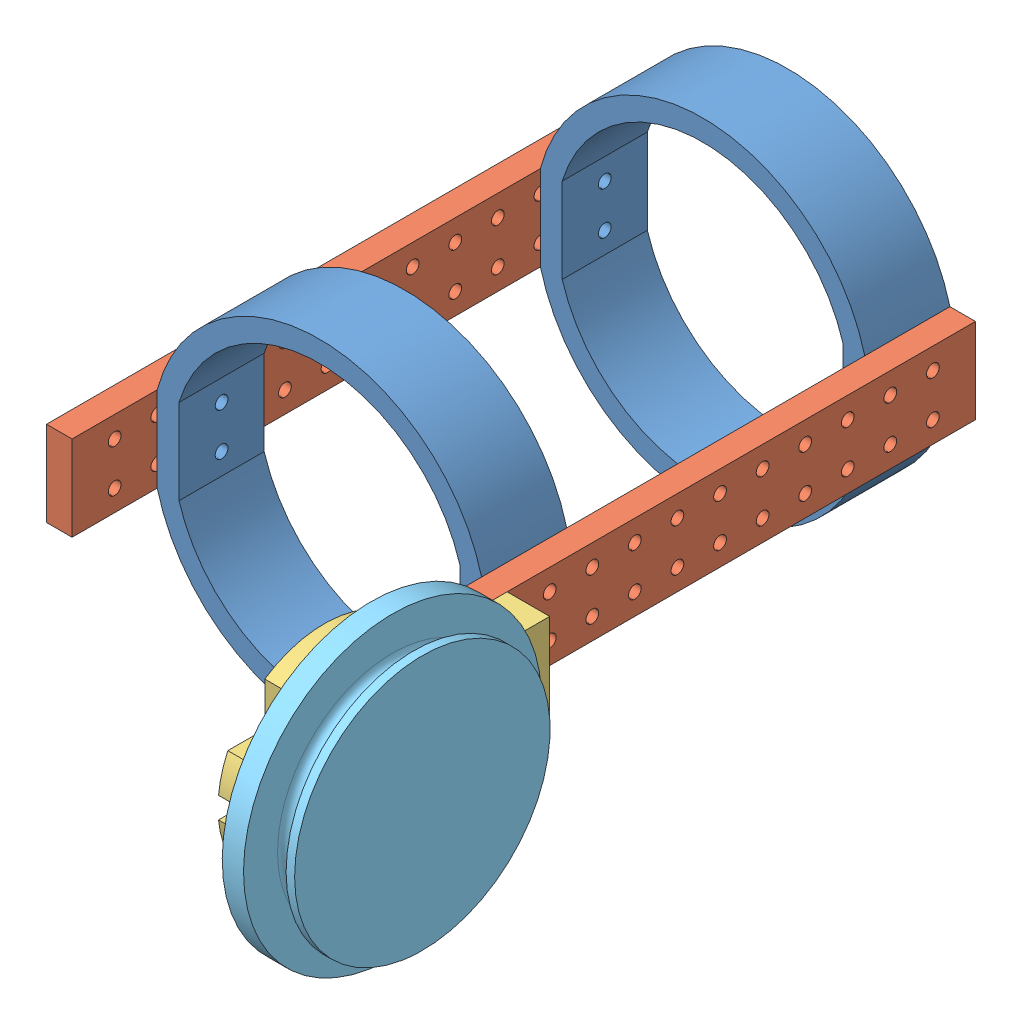
SolidWorks assembly Assem2, configuration Default. Lengths in mm.
Overall size (111.18 78.76 191.06).
9 component instances, 5 part files, 3 mates.
Components (placement in the parent):
- upper_arm_asm-1: upper_arm_asm [Default] at (2.8564 38.5972 -15.1439) size (88.18 78.76 130)
  - upper_arm_ring-1: upper_arm_ring [Default] at (38.6047 51.1661 38.7641) size (76.18 78.76 20)
  - upper_arm_beam-1: upper_arm_beam [Default] at (76.6957 49.3312 108.0302) x (0 0 -1) z (1 0 0) size (130 20 6)
  - upper_arm_beam-2: upper_arm_beam [Default] at (0.5137 49.3312 99.4981) x (0 0 1) z (-1 0 0) size (130 20 6)
  - upper_arm_ring-2: upper_arm_ring [Default] at (38.6047 51.1661 128.7641) size (76.18 78.76 20)
- elbow_joint-1: elbow_joint [Default] at (143.4165 50.2205 149.1506) x (0 0 1) z (-1 0 0) size (81.06 76.28 23)
  - joint_upper_22mmID-1: joint_upper_22mmID [Default] at (27.3835 39.5429 47.8644) size (67.79 50 10)
  - 22mm_BALL BEARING-1: 22mm_BALL BEARING [5972K91] at (27.3835 39.5429 52.3644) size (22 22 7)
  - joint_lower_8mmOD-1: joint_lower_8mmOD [Default] at (27.3835 39.5429 55.8644) x (0.094216 -0.995552 0) z (0 0 -1) size (70 70 21)
Mates (geometry in assembly coordinates):
- Coincident1: coincident: circle of upper_arm_asm-1/upper_arm_beam-1; circle of elbow_joint-1/joint_upper_22mmID-1
- Coincident2: coincident: plane of upper_arm_asm-1/upper_arm_beam-1 through (85.5521 87.9285 92.8863) normal (1 0 0); plane of elbow_joint-1/joint_upper_22mmID-1 through (85.5521 89.7633 176.5341) normal (-1 0 0)
- Coincident3: coincident anti-aligned: cylinder of upper_arm_asm-1/upper_arm_beam-1 through (85.5521 84.7633 143.6203) axis (-1 0 0) radius 1.5; circle of elbow_joint-1/joint_upper_22mmID-1
